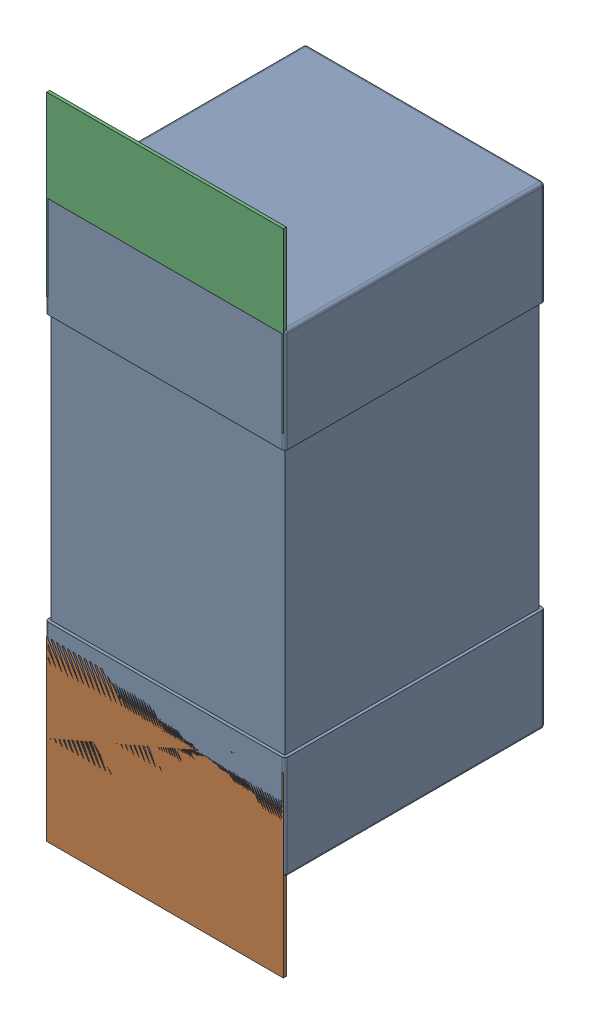
SolidWorks assembly C106, configuration Défaut. Lengths in mm.
Overall size (0.81 2.19 0.88).
5 component instances, 2 part files, 0 mates.
Components (placement in the parent):
- 0603_C-1: 0603_C [Défaut] at (7.4625 -9.4544 -2.0818) x (0 1 0) z (0 0 -1) size (1.6 0.81 0.88)
- 8260087904-1: 8260087904 [Défaut] at (7.4625 -9.7993 -2.0918) size (0.8 0.6 0.01)
  - Extruded_1211-1: Extruded_1211 [Défaut] at origin size (0.8 0.6 0.01)
- 8260087904-2: 8260087904 [Défaut] at (7.4625 -8.2044 -2.0918) size (0.8 0.6 0.01)
  - Extruded_1211-1: Extruded_1211 [Défaut] at origin size (0.8 0.6 0.01)
